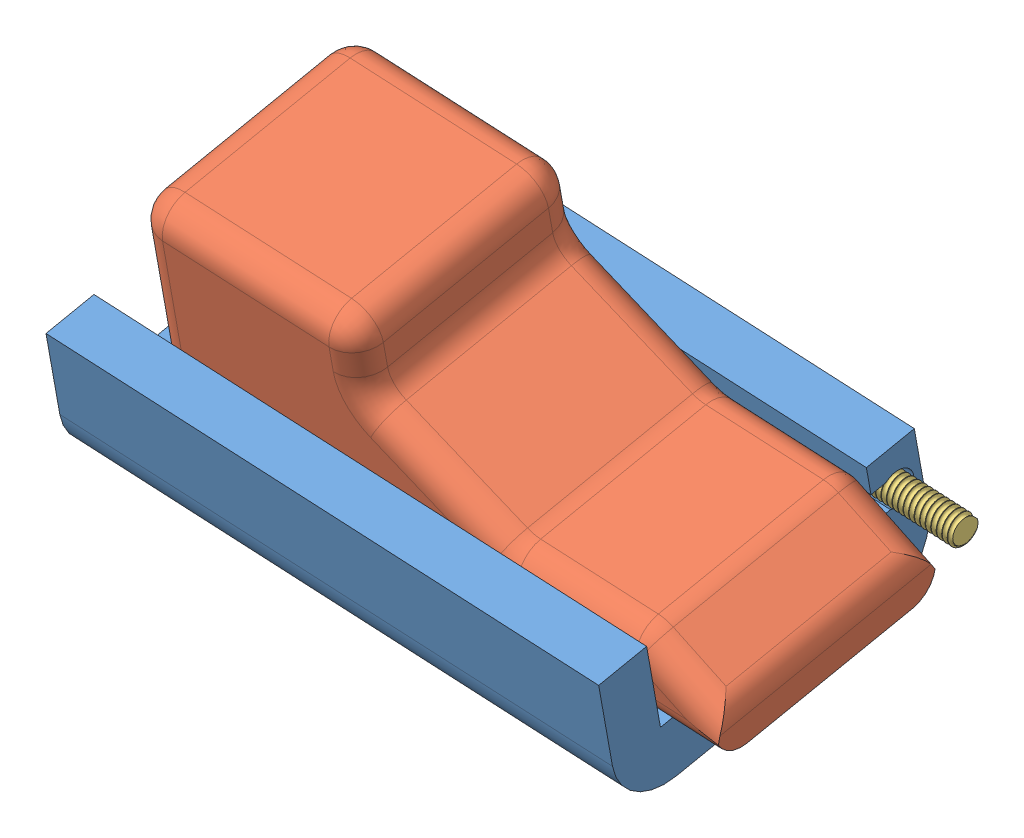
SolidWorks assembly Assem1, configuration Default. Lengths in mm.
Overall size (311.51 161.77 156.9).
4 component instances, 4 part files, 6 mates.
Components (placement in the parent):
- ShoeSole1-1: ShoeSole1 [Default] at (405.913 186.0418 243.2023) x (-0.998755 0.049857 -0.001462) z (0.012131 0.214377 -0.976676) size (254 63.5 146.3)
- Shoe-1: Shoe [Default] at (179.2246 195.5625 369.3235) x (0.998755 -0.049857 0.001462) z (-0.012131 -0.214377 0.976676) size (254 101.6 101.6)
- .5_10 Lead Screw-1: .5_10 Lead Screw [Default] at (134.1794 240.6113 263.1828) x (0.002261 0.015977 -0.99987) z (-0.049827 -0.998629 -0.01607) size (13.04 311.14 14.66)
- Nut3-2: Nut3 [Default] at (194.0351 237.6233 263.2705) x (0.012131 0.214377 -0.976676) z (-0.048381 -0.975478 -0.214715) size (18.84 127 15.33)
Mates (geometry in assembly coordinates):
- Concentric1: concentric aligned: cylinder of .5_10 Lead Screw-1 through (438.6 225.4148 263.6284) axis (-0.998755 0.049857 -0.001462) radius 6.35; cylinder of Nut3-2 through (320.877 231.2915 263.4561) axis (-0.998755 0.049857 -0.001462) radius 6.35
- Concentric2: concentric anti-aligned: cylinder of ShoeSole1-1 through (154.2413 239.6098 263.2122) axis (0.998755 -0.049857 0.001462) radius 7.62; cylinder of Nut3-2 through (320.877 231.2915 263.4561) axis (-0.998755 0.049857 -0.001462) radius 7.663
- Parallel1: parallel aligned: plane of ShoeSole1-1 through (408.7156 243.2201 278.5433) normal (-0.012131 -0.214377 0.976676); plane of Nut3-2 through (320.7415 228.8956 274.3714) normal (-0.012131 -0.214377 0.976676)
- Coincident3: coincident anti-aligned: plane of ShoeSole1-1 through (407.1419 210.819 248.656) normal (0.048381 0.975478 0.214715); plane of Shoe-1 through (179.2246 195.5625 369.3235) normal (-0.048381 -0.975478 -0.214715)
- Coincident4: coincident anti-aligned: plane of Shoe-1 through (182.3004 254.5089 278.2739) normal (0.012131 0.214377 -0.976676); plane of Nut3-2 through (320.7415 228.8956 274.3714) normal (-0.012131 -0.214377 0.976676)
- Coincident5: coincident anti-aligned: line of Shoe-1 through (193.5882 228.9505 272.8042) axis (0.048381 0.975478 0.214715); line of Nut3-2 through (194.2068 241.4217 275.5492) axis (-0.048381 -0.975478 -0.214715)
